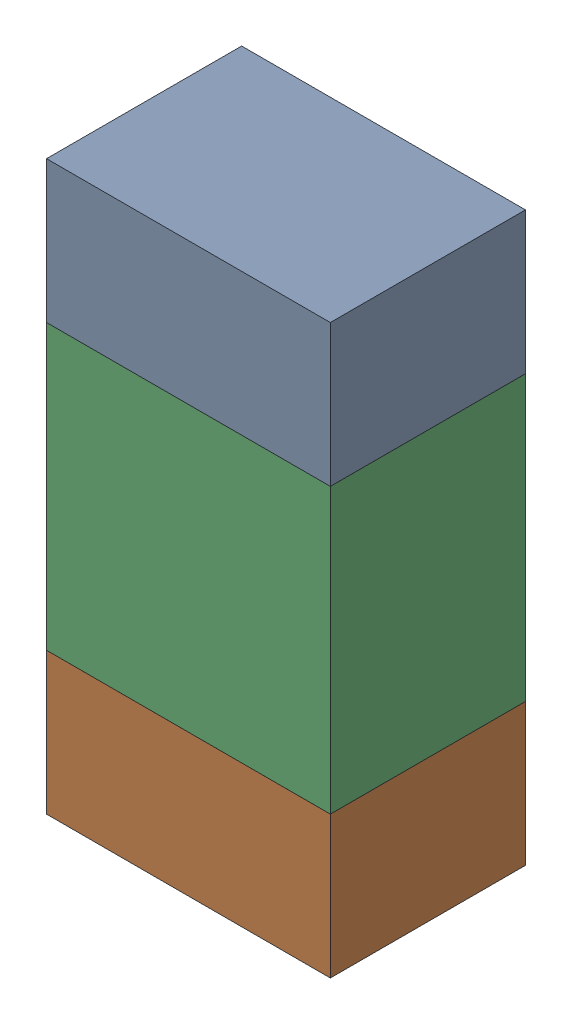
SolidWorks assembly R17, configuration ﾃﾞﾌｫﾙﾄ. Lengths in mm.
Overall size (0.8 1.6 0.55).
6 component instances, 2 part files, 0 mates.
Components (placement in the parent):
- 689261784-1: 689261784 [ﾃﾞﾌｫﾙﾄ] at (63.0001 53.0999 0) size (0.8 0.4 0.55)
  - Extruded_34-1: Extruded_34 [ﾃﾞﾌｫﾙﾄ] at origin size (0.8 0.4 0.55)
- 689261784-2: 689261784 [ﾃﾞﾌｫﾙﾄ] at (63.0001 51.8999 0) size (0.8 0.4 0.55)
  - Extruded_34-1: Extruded_34 [ﾃﾞﾌｫﾙﾄ] at origin size (0.8 0.4 0.55)
- 689261648-1: 689261648 [ﾃﾞﾌｫﾙﾄ] at (63.0001 52.5 0) size (0.8 0.8 0.55)
  - Extruded_33-1: Extruded_33 [ﾃﾞﾌｫﾙﾄ] at origin size (0.8 0.8 0.55)
